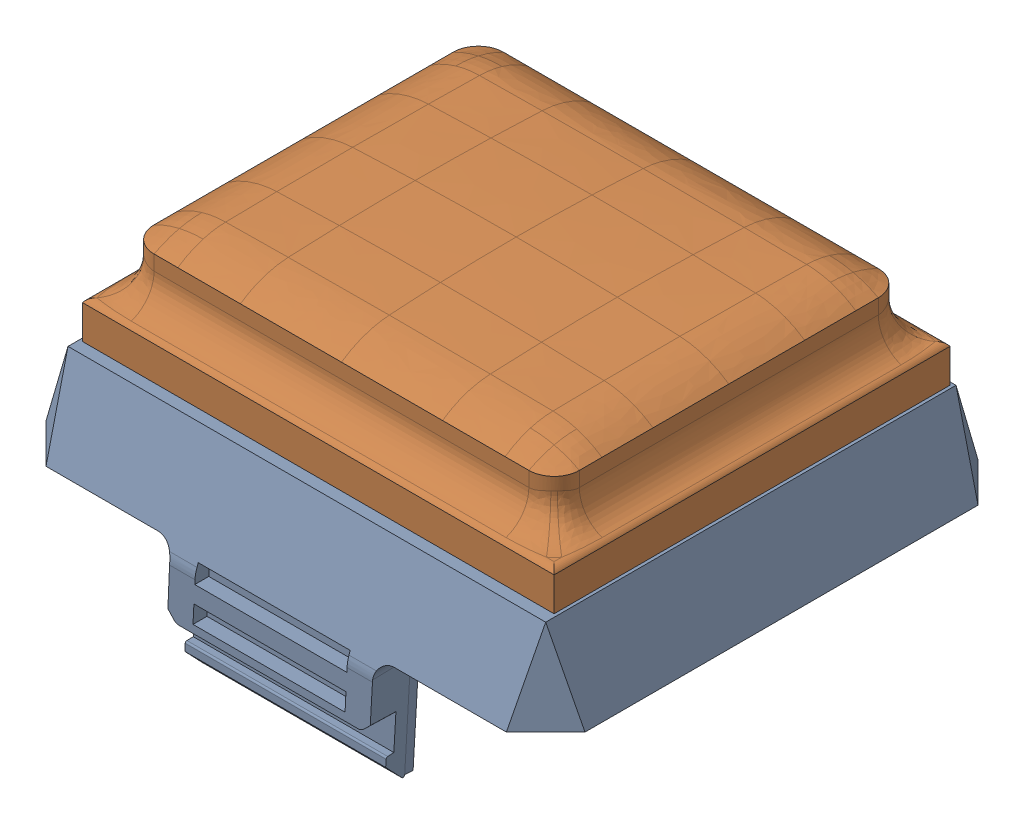
SolidWorks assembly BoardALL2, configuration 默认. Lengths in mm.
Overall size (32 17.53 28.9).
7 component instances, 7 part files, 17 mates.
Components (placement in the parent):
- Board3Con1612611Support-1: Board3Con1612611Support [默认] at origin size (32 12.05 28.9)
- Board3Con1612611OriginalSkin_TOP-1: Board3Con1612611OriginalSkin_TOP [默认] at (0 2 0) size (28.02 6.25 23.52) (hidden)
- Board3Con1612611Lens-1: Board3Con1612611Lens [默认] at (-1.1243 18 1.5226) x (1 0 0) z (0 -1 0) size (24.45 17.04 1)
- Board3Con1612lensside-1: Board3Con1612lensside [默认] at origin size (28.33 1.42 23.83)
- Board3Con1612downskinnew-1: Board3Con1612downskinnew [默认] at origin size (23.65 2.2 19.15)
- Boardholecutout-1: Boardholecutout [默认] at (0 2 0) size (23.8 4.28 19.29)
- chessboard-1: chessboard [默认] at (-4.7947 23.6 -14.6358) x (1 0 0) z (0 -1 0) size (22.5 16.35 0.4)
Mates (geometry in assembly coordinates):
- 重合1: coordinate: point of Support-1
- 重合8: coincident anti-aligned: plane of Support-1 through (-12.1625 18 0) normal (0.996195 0.087156 0); plane of 611Lens-1 through (-12.075 17 -10.5174) normal (-0.996195 -0.087156 0)
- 重合11: coincident anti-aligned: plane of 611Support-1 through (-13.75 19 11.5) normal (0 -0.34202 -0.939693); plane of lensside-1 through (-13.75 19 11.5) normal (0 0.34202 0.939693)
- 重合12: coincident anti-aligned: plane of 611Support-1 through (-13.75 19 12.7803) normal (0.939693 -0.34202 0); plane of lensside-1 through (-13.75 19 -11.5) normal (-0.939693 0.34202 0)
- 重合14: coincident anti-aligned: plane of 611Lens-1 through (-1.1243 18 1.5226) normal (0 1 0); plane of lensside-1 through (0 18 0) normal (0 -1 0)
- 重合15: coincident anti-aligned: plane of 611Lens-1 through (-1.1243 18 1.5226) normal (0 1 0); plane of downskinnew-1 through (0 18 0) normal (0 -1 0)
- 重合16: coincident anti-aligned: plane of lensside-1 through (-12.075 17.7531 -9.375) normal (1 0 0); plane of downskinnew-1 through (-12.075 17.7531 -9.375) normal (-1 0 0)
- 重合17: coincident anti-aligned: plane of 611OriginalSkin_TOP-1 through (-0.25 24 9.075) normal (0 0 -1); plane of downskinnew-1 through (-11.375 17.7531 9.075) normal (0 0 1)
- 重合18: coincident anti-aligned: plane of lensside-1 through (-11.375 17.7531 9.075) normal (0 0 -1); plane of downskinnew-1 through (-11.375 17.7531 9.075) normal (0 0 1)
- 重合21: coincident anti-aligned: plane of 611OriginalSkin_TOP-1 through (0 19 0) normal (0 -1 0); plane of lensside-1 through (0 19 0) normal (0 1 0)
- 同心1: concentric: cylinder of Board3Con1612downskinnew-1 through (-11.375 17.7531 -9.375) axis (0 1 0) radius 0.7; cylinder of Boardholecutout-1 through (-11.375 24 -9.375) axis (0 -1 0) radius 0.7
- 重合22: coincident: plane of Board3Con1612downskinnew-1 through (-12.075 17.7531 -9.375) normal (-1 0 0); plane of Boardholecutout-1 through (-12.075 24 8.375) normal (-1 0 0)
- 重合23: coincident anti-aligned: plane of Board3Con1612downskinnew-1 through (0 20.2 0) normal (0 1 0); plane of Boardholecutout-1 through (-11.375 20.2 -9.375) normal (0 -1 0)
- 平行1: parallel: plane of Board3Con1612lensside-1 through (0 19 0) normal (0 1 0); plane of chessboard-1 through (-4.9262 23.2 -2.3358) normal (0 -1 0)
- 重合25: coincident: plane of Boardholecutout-1 through (9 23.2 -0.32) normal (0 0 1); plane of chessboard-1 through (8.8685 23.2 -0.32) normal (0 0 -1)
- 重合26: coincident: plane of Boardholecutout-1 through (15.7053 23.2 -6.4358) normal (0 1 0); plane of chessboard-1 through (15.5738 23.2 -6.4358) normal (0 -1 0)
- 重合27: coincident anti-aligned: plane of Boardholecutout-1 through (11 23.2 1.68) normal (-1 0 0); plane of chessboard-1 through (10.8685 23.2 1.68) normal (1 0 0)
